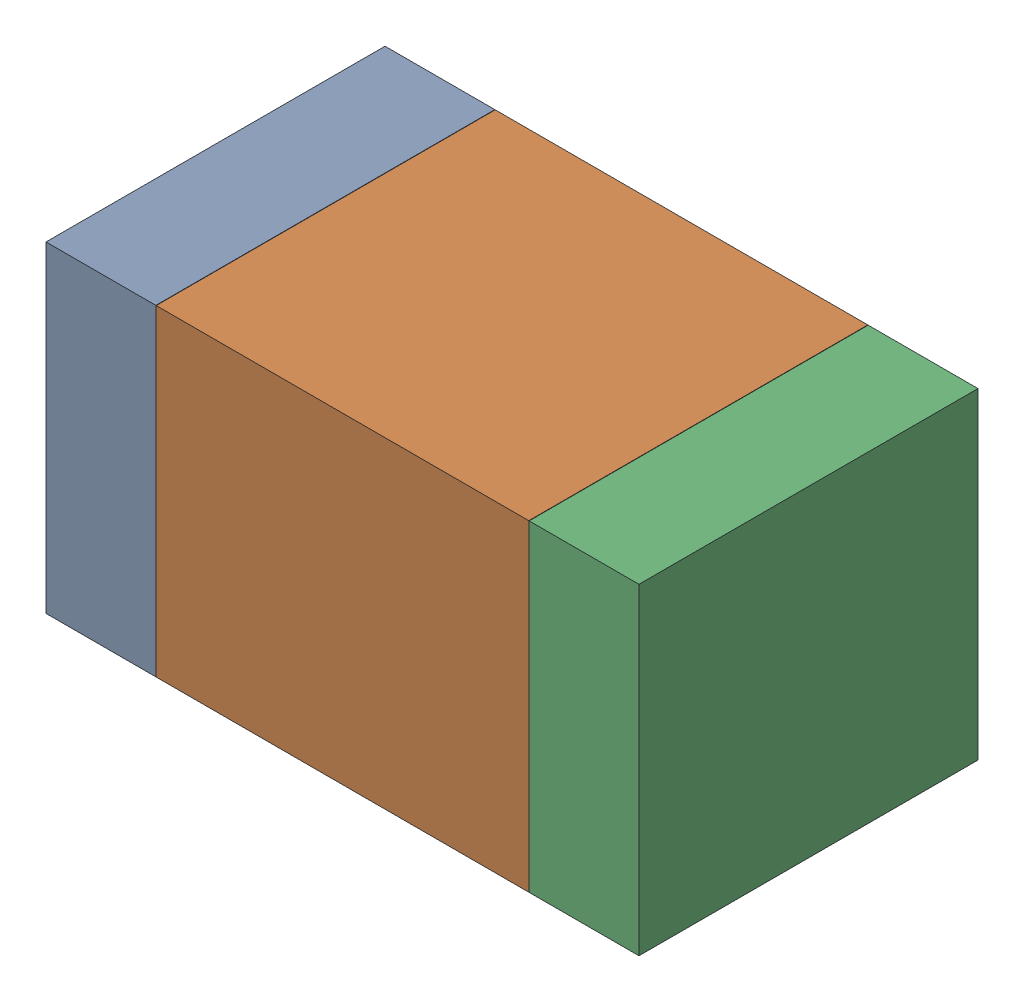
SolidWorks assembly C13, configuration Default. Lengths in mm.
Overall size (1.75 0.95 1).
6 component instances, 2 part files, 0 mates.
Components (placement in the parent):
- 6575498272-1: 6575498272 [Default] at (30.5295 25.908 0) size (0.32 0.95 1)
  - Extruded_8-1: Extruded_8 [Default] at origin size (0.32 0.95 1)
- 6575498112-1: 6575498112 [Default] at (31.242 25.908 0) size (1.1 0.95 1)
  - Extruded_9-1: Extruded_9 [Default] at origin size (1.1 0.95 1)
- 6575498272-2: 6575498272 [Default] at (31.9545 25.908 0) size (0.32 0.95 1)
  - Extruded_8-1: Extruded_8 [Default] at origin size (0.32 0.95 1)
